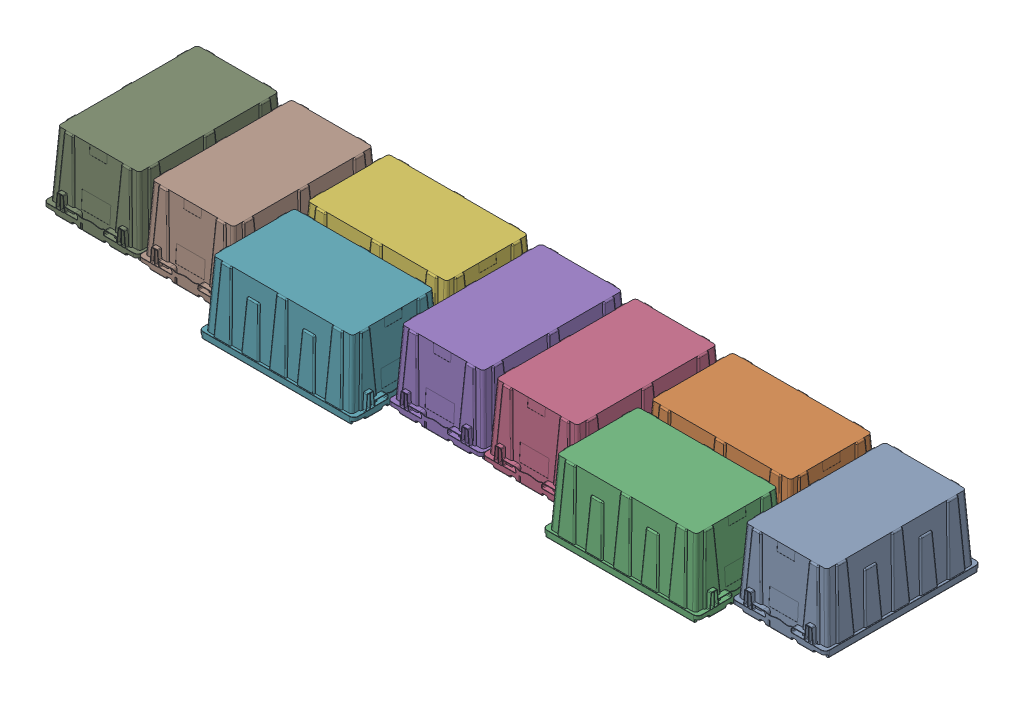
SolidWorks assembly LANDFILL_GP2_ASM, configuration Default. Lengths in mm.
Overall size (3422.65 313.83 831.85).
9 component instances, 1 part files, 0 mates.
Components (placement in the parent):
- GRAY_TOTE-1: GRAY_TOTE [Default] at (-206.375 0 -339.725) x (0 -1 0) z (0 0 1) size (313.83 412.75 692.15)
- GRAY_TOTE-2: GRAY_TOTE [Default] at (-752.475 0 -473.075) x (0 -1 0) z (1 0 0) size (313.83 412.75 692.15)
- GRAY_TOTE-3: GRAY_TOTE [Default] at (-752.475 0 -60.325) x (0 -1 0) z (1 0 0) size (313.83 412.75 692.15)
- GRAY_TOTE-4: GRAY_TOTE [Default] at (-1298.575 0 -339.725) x (0 -1 0) z (0 0 -1) size (313.83 412.75 692.15)
- GRAY_TOTE-5: GRAY_TOTE [Default] at (-1711.325 0 -339.725) x (0 -1 0) z (0 0 -1) size (313.83 412.75 692.15)
- GRAY_TOTE-6: GRAY_TOTE [Default] at (-2257.425 0 -473.075) x (0 -1 0) z (1 0 0) size (313.83 412.75 692.15)
- GRAY_TOTE-7: GRAY_TOTE [Default] at (-2257.425 0 -60.325) x (0 -1 0) z (1 0 0) size (313.83 412.75 692.15)
- GRAY_TOTE-8: GRAY_TOTE [Default] at (-2803.525 0 -339.725) x (0 -1 0) z (0 0 -1) size (313.83 412.75 692.15)
- GRAY_TOTE-9: GRAY_TOTE [Default] at (-3216.275 0 -339.725) x (0 -1 0) z (0 0 -1) size (313.83 412.75 692.15)
